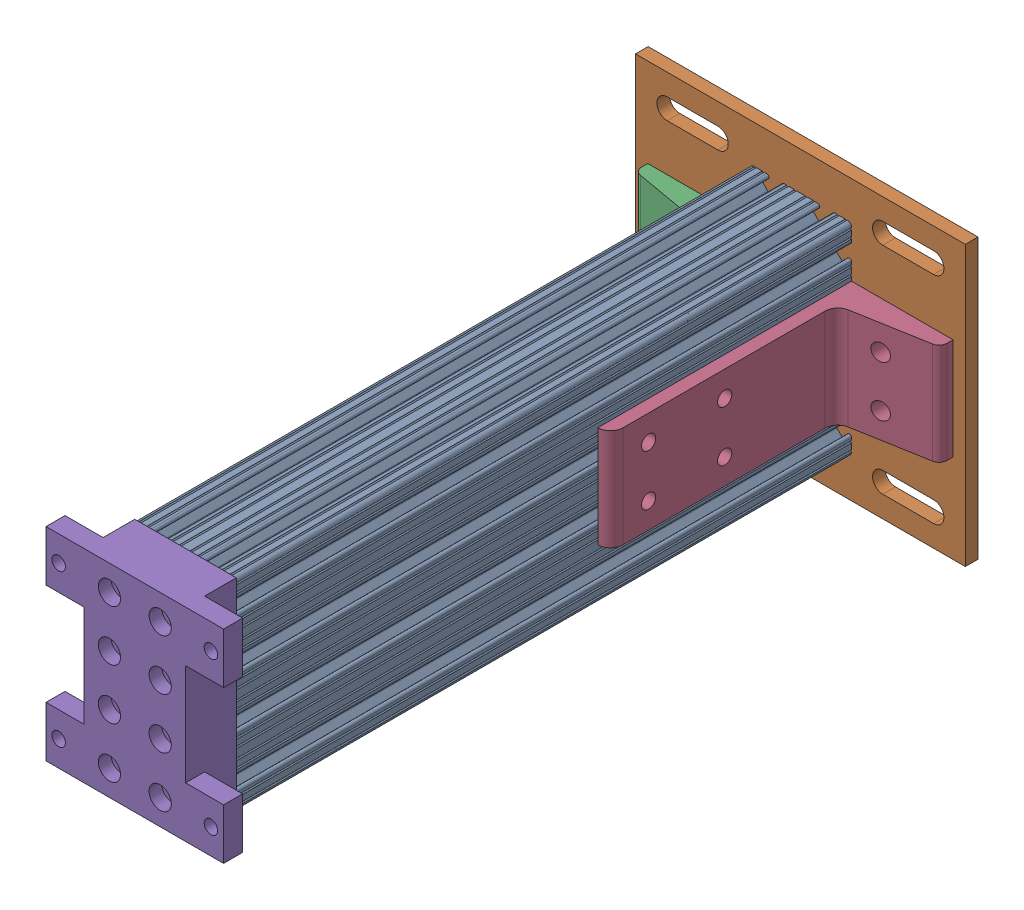
SolidWorks assembly Mirrorbreadboard support leg assembly3, configuration Default. Lengths in mm.
Overall size (165.1 139.7 339.72).
6 component instances, 4 part files, 6 mates.
Components (placement in the parent):
- Mirror8020-2040 leg for breadboard support-1: Mirror8020-2040 leg for breadboard support [Default] at (-48.9055 -77.0614 -78.1612) size (50.8 101.6 307.98)
- Mirror8020-2387-DEFAULT3-1: Mirror8020-2387-DEFAULT3 [Default] at (-34.9863 -22.6888 -91.8816) x (0 1 0) z (1 0 0) size (139.7 133.35 165.1)
  - Mirror8020-2387-DEFAULT_238708-1: Mirror8020-2387-DEFAULT_238708 [Default] at (-67.1549 7.3704 -27.8119) size (139.7 6.35 165.1)
  - Mirror8020-2387-DEFAULT_238509-1: Mirror8020-2387-DEFAULT_238509 [Default] at (9.1264 0.0214 -49.7635) x (0 0 -1) z (1 0 0) size (50.8 127 50.8)
  - Mirror8020-2387-DEFAULT_238509-2: Mirror8020-2387-DEFAULT_238509 [Default] at (-41.6736 0.0214 46.9187) x (0 0 1) z (-1 0 0) size (50.8 127 50.8)
- Mirrorbreadboard support leg top bracket-1: Mirrorbreadboard support leg top bracket [Default] at (-61.6055 -89.7614 229.8138) x (0 1 0) z (1 0 0) size (101.6 25.4 88.9)
Mates (geometry in assembly coordinates):
- Coincident1: coincident anti-aligned: plane of Mirror8020-2040 leg for breadboard support-1 through (-61.6055 -36.3198 -78.1612) normal (0 0 -1); plane of Mirror8020-2387-DEFAULT3-1/Mirror8020-2387-DEFAULT_238708-1 through (-36.4088 -207.3239 -78.1612) normal (0 0 1)
- Coincident2: coincident anti-aligned: plane of Mirror8020-2040 leg for breadboard support-1 through (-10.8056 -41.095 229.8138) normal (1 0 0); plane of Mirror8020-2387-DEFAULT3-1/Mirror8020-2387-DEFAULT_238509-2 through (-10.8056 -13.5624 -150.9329) normal (-1 0 0)
- Distance1: distance = 19.05 mm aligned: plane of Mirror8020-2387-DEFAULT3-1/Mirror8020-2387-DEFAULT_238708-1 through (-36.4088 -108.8114 -78.1612) normal (0 -1 0); plane of Mirror8020-2040 leg for breadboard support-1 through (-38.3391 -89.7614 229.8138) normal (0 -1 0)
- Coincident3: coincident anti-aligned: plane of Mirror8020-2040 leg for breadboard support-1 through (-61.6055 -36.3198 229.8138) normal (0 0 1); plane of Mirrorbreadboard support leg top bracket-1 through (-10.8055 -89.7614 229.8138) normal (0 0 -1)
- Concentric1: concentric anti-aligned: circle of Mirror8020-2040 leg for breadboard support-1; circle of Mirrorbreadboard support leg top bracket-1
- Concentric2: concentric anti-aligned: circle of Mirror8020-2040 leg for breadboard support-1; circle of Mirrorbreadboard support leg top bracket-1
